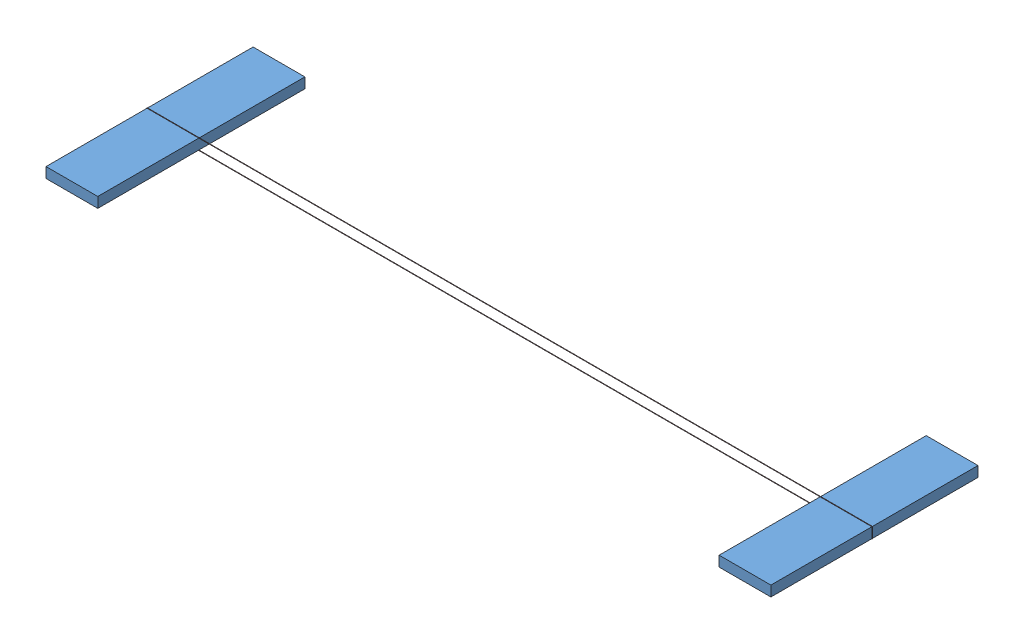
SolidWorks assembly assembly, configuration Default. Lengths in mm.
Overall size (28.03 0.43 8).
3 component instances, 3 part files, 2 mates.
Components (placement in the parent):
- supports-1: supports [Default] at (-0.8698 13.4714 16.718) size (28 0.4 8)
- fibre-1: fibre [Default] at (27.1302 13.8714 14.6125) x (0 0 1) z (0 -1 0) size (0.02 28.03 0.43)
- hydrogel-1: hydrogel [Default] at (-2.625 12.6412 25.1957) x (0 0 -1) z (1 0 0) size (9 3 30) (hidden)
Mates (geometry in assembly coordinates):
- Tangent1: tangent anti-aligned: plane of supports-1 through (-0.8698 13.4714 24.718) normal (-1 0 0); cylinder of fibre-1 through (-0.8773 13.4714 20.8125) axis (0 1 0) radius 0.0075
- Tangent2: tangent anti-aligned: plane of supports-1 through (-0.8698 13.8714 24.718) normal (0 1 0); cylinder of fibre-1 through (-0.8698 13.8789 20.8125) axis (1 0 0) radius 0.0075
